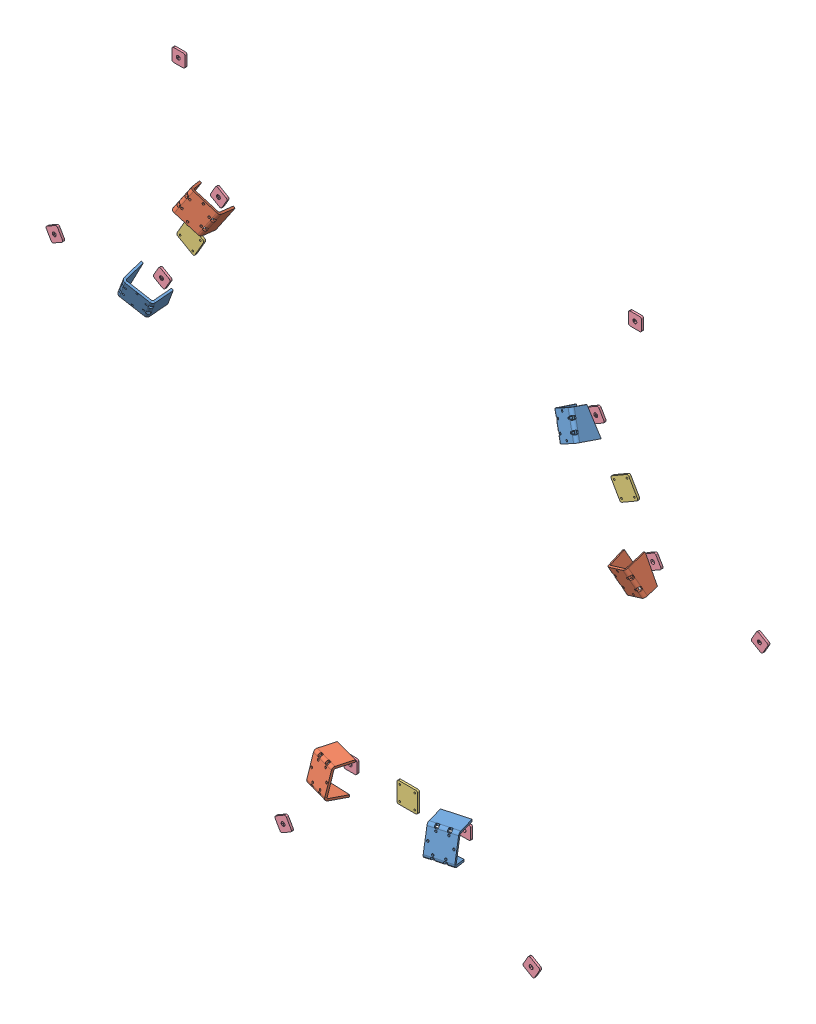
SolidWorks assembly Frame onder Assembly, configuration Default. Lengths in mm.
Overall size (2108.24 1827.1 105.7).
23 component instances, 6 part files, 67 mates.
Components (placement in the parent):
- Frame onder-1: Frame onder [Default<As Machined>] at (1582.846 283.0348 267.4201) x (1 0 0) z (0 -1 0) size (2136.91 40 1851.93) (hidden)
- Base left-12: Base left [Default] at (1519.9566 294.7705 359.3913) x (-0.963822 0 0.266548) z (0.064484 -0.970296 0.23317) size (75 61.12 94.89)
- Base left-13: Base left [Default] at (649.454 1310.2395 359.3913) x (0.481911 0.834694 0.266548) z (-0.872543 0.429303 0.23317) size (75 61.12 94.89)
- Base left-14: Base left [Default] at (1964.1273 1556.3824 359.3913) x (0.481911 -0.834694 0.266548) z (0.808059 0.540992 0.23317) size (75 61.12 94.89)
- Base right-8: Base right [Default] at (1240.2492 362.6912 343.0694) x (0.963822 0 0.266548) z (0.064484 0.970296 -0.23317) size (75 61.12 94.89)
- Base right-9: Base right [Default] at (848.1288 1518.5129 343.0694) x (-0.481911 -0.834694 0.266548) z (0.808059 -0.540992 -0.23317) size (75 61.12 94.89)
- Base right-10: Base right [Default] at (2045.16 1280.1882 343.0694) x (-0.481911 0.834694 0.266548) z (-0.872543 -0.429303 -0.23317) size (75 61.12 94.89)
- Wielplaat-1: Wielplaat [Default] at (1407.846 293.0348 261.4201) x (1 0 0) z (0 -1 0) size (60 6 60)
- Wielplaat-2: Wielplaat [Default] at (2051.6857 1408.198 261.4201) x (0.866025 0.5 0) z (0.5 -0.866025 0) size (60 6 60)
- Wielplaat-3: Wielplaat [Default] at (755.9678 1378.198 261.4201) x (0.866025 -0.5 0) z (-0.5 -0.866025 0) size (60 6 60)
- Voetplaat-1: Voetplaat [Default] at (1562.846 304.0348 261.4201) size (38 38 7.17)
- Voetplaat-2: Voetplaat [Default] at (1230.846 304.0348 261.4201) size (38 38 7.17)
- Voetplaat-3: Voetplaat [Default] at (668.9415 1249.464 261.4201) x (0.866025 -0.5 0) z (0 0 1) size (38 38 7.17)
- Voetplaat-4: Voetplaat [Default] at (834.9415 1536.9845 261.4201) x (0.866025 -0.5 0) z (0 0 1) size (38 38 7.17)
- Voetplaat-5: Voetplaat [Default] at (1953.6594 1555.9845 261.4201) x (0.866025 0.5 0) z (0 0 1) size (38 38 7.17)
- Voetplaat-6: Voetplaat [Default] at (2119.6594 1268.464 261.4201) x (0.866025 0.5 0) z (0 0 1) size (38 38 7.17)
- Voetplaat-7: Voetplaat [Default] at (2412.2111 1201.5374 261.4201) x (0.866025 -0.5 0) z (0 0 1) size (38 38 7.17)
- Voetplaat-8: Voetplaat [Default] at (2060.9751 1837.7139 261.4201) size (38 38 7.17)
- Voetplaat-9: Voetplaat [Default] at (729.6913 1837.7139 261.4201) size (38 38 7.17)
- Voetplaat-10: Voetplaat [Default] at (374.877 1223.1576 261.4201) x (0.866025 0.5 0) z (0 0 1) size (38 38 7.17)
- Voetplaat-11: Voetplaat [Default] at (1042.0317 67.6118 261.4201) x (0.866025 0.5 0) z (0 0 1) size (38 38 7.17)
- Voetplaat-12: Voetplaat [Default] at (1746.5692 48.6118 261.4201) x (0.866025 -0.5 0) z (0 0 1) size (38 38 7.17)
- M6 moer-1: M6 moer [Default] at (1934.2001 1595.5407 337.2844) x (-0.911999 0.2083 -0.353368) z (-0.338825 0.103019 0.935192) size (11.95 11.95 6.5)
Mates (geometry in assembly coordinates):
- Coincident36: coincident: plane of Frame onder-1 through (2146.1139 1260.6435 307.4201) normal (0 0 1); line of Base left-14 through (1937.6445 1614.3496 307.4201) axis (0.536083 -0.844165 0)
- Coincident47: coincident: plane of Frame onder-1 through (814.578 1615.7139 307.4201) normal (0 0 1); line of Base left-13 through (612.4943 1258.3211 307.4201) axis (0.463027 0.886344 0)
- Coincident51: coincident: plane of Frame onder-1 through (1172.846 285.0348 307.4201) normal (0 0 1); line of Base left-12 through (1583.3991 288.7216 307.4201) axis (-0.99911 -0.042179 0)
- Coincident61: coincident: plane of Frame onder-1 through (814.578 1615.7139 307.4201) normal (0 0 1); line of Base right-9 through (776.2948 1548.6022 307.4201) axis (0.536083 0.844165 0)
- Coincident67: coincident: plane of Frame onder-1 through (2146.1139 1260.6435 307.4201) normal (0 0 1); line of Base right-10 through (2107.135 1327.3537 307.4201) axis (0.463027 -0.886344 0)
- Coincident74: coincident anti-aligned: plane of Frame onder-1 through (1172.846 363.0348 269.4201) normal (0 1 0); plane of Base left-12 through (1533.9839 363.0348 410.113) normal (0 -1 0)
- Coincident76: coincident: point of Frame onder-1; line of Base left-12 through (1574.2848 363.0348 274.4633) axis (0.266548 0 0.963822)
- Coincident77: coincident anti-aligned: plane of Frame onder-1 through (2078.5639 1221.6435 269.4201) normal (-0.866025 -0.5 0); plane of Base left-14 through (1897.995 1534.3981 410.113) normal (0.866025 0.5 0)
- Coincident78: coincident: point of Frame onder-1; line of Base left-14 through (1877.8445 1569.2997 274.4633) axis (-0.133274 0.230837 0.963822)
- Coincident79: coincident anti-aligned: plane of Frame onder-1 through (882.128 1576.7139 269.4201) normal (0.866025 -0.5 0); plane of Base left-13 through (701.5591 1263.9594 410.113) normal (-0.866025 0.5 0)
- Coincident80: coincident: point of Frame onder-1; line of Base left-13 through (681.4086 1229.0577 274.4633) axis (-0.133274 -0.230837 0.963822)
- Coincident81: coincident anti-aligned: plane of Frame onder-1 through (2078.5639 1221.6435 269.4201) normal (-0.866025 -0.5 0); plane of Base right-10 through (2044.8037 1280.1179 342.6454) normal (0.866025 0.5 0)
- Coincident82: coincident: point of Frame onder-1; line of Base right-10 through (2080.6819 1217.9752 320.7367) axis (-0.133274 0.230837 -0.963822)
- Coincident85: coincident anti-aligned: plane of Frame onder-1 through (882.128 1576.7139 269.4201) normal (0.866025 -0.5 0); plane of Base right-9 through (848.3678 1518.2395 342.6454) normal (-0.866025 0.5 0)
- Coincident86: coincident: point of Frame onder-1; line of Base right-9 through (884.2459 1580.3823 320.7367) axis (-0.133274 -0.230837 -0.963822)
- Coincident89: coincident: plane of Frame onder-1 through (1172.846 285.0348 307.4201) normal (0 0 1); line of Base right-8 through (1250.1081 285.4364 307.4201) axis (-0.99911 0.042179 0)
- Coincident90: coincident anti-aligned: plane of Frame onder-1 through (1172.846 363.0348 269.4201) normal (0 1 0); plane of Base right-8 through (1240.3664 363.0348 342.6454) normal (0 -1 0)
- Coincident91: coincident: point of Frame onder-1; line of Base right-8 through (1168.6101 363.0348 320.7367) axis (0.266548 0 -0.963822)
- Coincident92: coincident anti-aligned: plane of Frame onder-1 through (1172.846 285.0348 267.4201) normal (0 0 -1); plane of Wielplaat-1 through (1352.846 298.0348 267.4201) normal (0 0 1)
- Distance2: distance = 10 mm aligned: plane of Wielplaat-1 through (1402.846 293.0348 267.4201) normal (0 -1 0); plane of Frame onder-1 through (1172.846 283.0348 269.4201) normal (0 -1 0)
- Distance3: distance = 175 mm: plane of Wielplaat-1 through (1407.846 298.0348 267.4201) normal (1 0 0); line of Frame onder-1 through (1582.846 361.0348 267.4201) axis (0 -1 0)
- Coincident94: coincident anti-aligned: plane of Frame onder-1 through (2146.1139 1260.6435 267.4201) normal (0 0 -1); plane of Wielplaat-2 through (2001.5543 1385.0281 267.4201) normal (0 0 1)
- Parallel1: parallel aligned: plane of Frame onder-1 through (2147.846 1261.6435 269.4201) normal (0.866025 0.5 0); plane of Wielplaat-2 through (2049.1857 1412.5281 267.4201) normal (0.866025 0.5 0)
- Distance5: distance = 175 mm: plane of Wielplaat-2 through (2047.3556 1405.698 267.4201) normal (0.5 -0.866025 0); line of Frame onder-1 through (2080.296 1222.6435 267.4201) axis (0.866025 0.5 0)
- Distance6: distance = 10 mm aligned: plane of Wielplaat-2 through (2049.1857 1412.5281 267.4201) normal (0.866025 0.5 0); plane of Frame onder-1 through (2147.846 1261.6435 269.4201) normal (0.866025 0.5 0)
- Coincident95: coincident anti-aligned: plane of Frame onder-1 through (814.578 1615.7139 267.4201) normal (0 0 -1); plane of Wielplaat-3 through (710.8364 1410.0281 267.4201) normal (0 0 1)
- Parallel2: parallel aligned: plane of Frame onder-1 through (812.846 1616.7139 269.4201) normal (-0.866025 0.5 0); plane of Wielplaat-3 through (706.5062 1412.5281 267.4201) normal (-0.866025 0.5 0)
- Distance7: distance = 10 mm aligned: plane of Wielplaat-3 through (706.5062 1412.5281 267.4201) normal (-0.866025 0.5 0); plane of Frame onder-1 through (812.846 1616.7139 269.4201) normal (-0.866025 0.5 0)
- Distance8: distance = 175 mm: plane of Wielplaat-3 through (781.6376 1432.6595 267.4201) normal (0.5 0.866025 0); line of Frame onder-1 through (878.6639 1578.7139 267.4201) axis (-0.866025 0.5 0)
- Coincident96: coincident anti-aligned: plane of Frame onder-1 through (1172.846 285.0348 267.4201) normal (0 0 -1); plane of Voetplaat-1 through (1529.846 309.0348 267.4201) normal (0 0 1)
- Distance9: distance = 21 mm aligned: plane of Voetplaat-1 through (1557.846 304.0348 267.4201) normal (0 -1 0); plane of Frame onder-1 through (1172.846 283.0348 269.4201) normal (0 -1 0)
- Distance10: distance = 20 mm: plane of Voetplaat-1 through (1562.846 309.0348 267.4201) normal (1 0 0); line of Frame onder-1 through (1582.846 361.0348 267.4201) axis (0 -1 0)
- Distance11: distance = 21 mm aligned: plane of Voetplaat-2 through (1225.846 304.0348 267.4201) normal (0 -1 0); plane of Frame onder-1 through (1172.846 283.0348 269.4201) normal (0 -1 0)
- Distance12: distance = 20 mm: plane of Voetplaat-2 through (1192.846 309.0348 267.4201) normal (-1 0 0); line of Frame onder-1 through (1172.846 359.0348 267.4201) axis (0 -1 0)
- Coincident103: coincident anti-aligned: plane of Frame onder-1 through (1172.846 285.0348 267.4201) normal (0 0 -1); plane of Voetplaat-2 through (1197.846 309.0348 267.4201) normal (0 0 1)
- Distance14: distance = 21 mm aligned: plane of Voetplaat-3 through (638.5325 1272.7942 267.4201) normal (-0.866025 0.5 0); plane of Frame onder-1 through (812.846 1616.7139 269.4201) normal (-0.866025 0.5 0)
- Distance15: distance = 20 mm: plane of Voetplaat-3 through (664.6113 1251.964 267.4201) normal (-0.5 -0.866025 0); line of Frame onder-1 through (611.3101 1259.6435 267.4201) axis (0.866025 -0.5 0)
- Coincident107: coincident anti-aligned: plane of Frame onder-1 through (814.578 1615.7139 267.4201) normal (0 0 -1); plane of Voetplaat-3 through (642.8626 1270.2942 267.4201) normal (0 0 1)
- Distance16: distance = 21 mm aligned: plane of Voetplaat-4 through (804.5325 1560.3146 267.4201) normal (-0.866025 0.5 0); plane of Frame onder-1 through (812.846 1616.7139 269.4201) normal (-0.866025 0.5 0)
- Distance17: distance = 20 mm: plane of Voetplaat-4 through (849.6113 1572.3934 267.4201) normal (0.5 0.866025 0); line of Frame onder-1 through (878.6639 1578.7139 267.4201) axis (-0.866025 0.5 0)
- Coincident111: coincident anti-aligned: plane of Frame onder-1 through (814.578 1615.7139 267.4201) normal (0 0 -1); plane of Voetplaat-4 through (808.8626 1557.8146 267.4201) normal (0 0 1)
- Coincident112: coincident anti-aligned: plane of Frame onder-1 through (2146.1139 1260.6435 267.4201) normal (0 0 -1); plane of Voetplaat-5 through (1922.5806 1543.8146 267.4201) normal (0 0 1)
- Distance18: distance = 21 mm aligned: plane of Voetplaat-5 through (1951.1594 1560.3146 267.4201) normal (0.866025 0.5 0); plane of Frame onder-1 through (2147.846 1261.6435 269.4201) normal (0.866025 0.5 0)
- Distance19: distance = 20 mm: plane of Voetplaat-5 through (1930.3293 1586.3934 267.4201) normal (-0.5 0.866025 0); line of Frame onder-1 through (1939.3819 1614.7139 267.4201) axis (-0.866025 -0.5 0)
- Coincident117: coincident anti-aligned: plane of Frame onder-1 through (2146.1139 1260.6435 267.4201) normal (0 0 -1); plane of Voetplaat-6 through (2088.5806 1256.2942 267.4201) normal (0 0 1)
- Distance20: distance = 21 mm aligned: plane of Voetplaat-6 through (2117.1594 1272.7942 267.4201) normal (0.866025 0.5 0); plane of Frame onder-1 through (2147.846 1261.6435 269.4201) normal (0.866025 0.5 0)
- Distance21: distance = 20 mm: plane of Voetplaat-6 through (2115.3293 1265.964 267.4201) normal (0.5 -0.866025 0); line of Frame onder-1 through (2082.028 1223.6435 267.4201) axis (0.866025 0.5 0)
- Distance22: distance = 1 mm aligned: plane of Voetplaat-8 through (2055.9751 1875.7139 267.4201) normal (0 1 0); plane of Frame onder-1 through (687.846 1876.7139 269.4201) normal (0 1 0)
- Coincident121: coincident anti-aligned: plane of Frame onder-1 through (687.846 1838.7139 267.4201) normal (0 0 -1); plane of Voetplaat-8 through (2027.9751 1842.7139 267.4201) normal (0 0 1)
- Distance23: distance = 5 mm: plane of Voetplaat-8 through (2060.9751 1842.7139 267.4201) normal (1 0 0); point of Frame onder-1
- Coincident123: coincident anti-aligned: plane of Frame onder-1 through (687.846 1838.7139 267.4201) normal (0 0 -1); plane of Voetplaat-9 through (696.6913 1842.7139 267.4201) normal (0 0 1)
- Distance24: distance = 1 mm aligned: plane of Voetplaat-9 through (724.6913 1875.7139 267.4201) normal (0 1 0); plane of Frame onder-1 through (687.846 1876.7139 269.4201) normal (0 1 0)
- Distance25: distance = 5 mm: plane of Voetplaat-9 through (691.6913 1842.7139 267.4201) normal (-1 0 0); point of Frame onder-1
- Coincident126: coincident anti-aligned: plane of Frame onder-1 through (1043.0883 63.7816 267.4201) normal (0 0 -1); plane of Voetplaat-10 through (343.7982 1210.9877 267.4201) normal (0 0 1)
- Distance26: distance = 1 mm aligned: plane of Voetplaat-10 through (339.468 1208.4877 267.4201) normal (-0.866025 -0.5 0); plane of Frame onder-1 through (1010.1794 44.7816 269.4201) normal (-0.866025 -0.5 0)
- Distance27: distance = 5 mm: plane of Voetplaat-10 through (351.5469 1253.5666 267.4201) normal (-0.5 0.866025 0); point of Frame onder-1
- Coincident129: coincident anti-aligned: plane of Frame onder-1 through (1043.0883 63.7816 267.4201) normal (0 0 -1); plane of Voetplaat-11 through (1010.9529 55.4419 267.4201) normal (0 0 1)
- Distance28: distance = 1 mm aligned: plane of Voetplaat-11 through (1006.6227 52.9419 267.4201) normal (-0.866025 -0.5 0); plane of Frame onder-1 through (1010.1794 44.7816 269.4201) normal (-0.866025 -0.5 0)
- Distance29: distance = 5 mm: plane of Voetplaat-11 through (1037.7016 65.1118 267.4201) normal (0.5 -0.866025 0); point of Frame onder-1
- Coincident132: coincident anti-aligned: plane of Frame onder-1 through (2401.0908 1256.2765 267.4201) normal (0 0 -1); plane of Voetplaat-12 through (1720.4904 69.4419 267.4201) normal (0 0 1)
- Distance30: distance = 1 mm aligned: plane of Voetplaat-12 through (1749.0692 52.9419 267.4201) normal (0.866025 -0.5 0); plane of Frame onder-1 through (2433.9998 1237.2765 269.4201) normal (0.866025 -0.5 0)
- Distance31: distance = 5 mm: point of Frame onder-1; plane of Voetplaat-12 through (1742.2391 51.1118 267.4201) normal (-0.5 -0.866025 0)
- Coincident135: coincident anti-aligned: plane of Frame onder-1 through (2401.0908 1256.2765 267.4201) normal (0 0 -1); plane of Voetplaat-7 through (2386.1323 1222.3675 267.4201) normal (0 0 1)
- Distance32: distance = 1 mm aligned: plane of Voetplaat-7 through (2414.7111 1205.8675 267.4201) normal (0.866025 -0.5 0); plane of Frame onder-1 through (2433.9998 1237.2765 269.4201) normal (0.866025 -0.5 0)
- Distance33: distance = 5 mm: point of Frame onder-1; plane of Voetplaat-7 through (2426.881 1236.9463 267.4201) normal (0.5 0.866025 0)
- Concentric1: concentric anti-aligned: cylinder of M6 moer-1 through (1932.506 1596.0558 341.9604) axis (0.338825 -0.103019 -0.935192) radius 3; cylinder of Base left-14 through (1933.353 1595.7982 339.6224) axis (-0.338825 0.103019 0.935192) radius 3
- Coincident137: coincident anti-aligned: plane of Base left-14 through (1964.1273 1556.3824 359.3913) normal (0.338825 -0.103019 -0.935192); plane of M6 moer-1 through (1931.9977 1596.2103 343.3632) normal (-0.338825 0.103019 0.935192)
